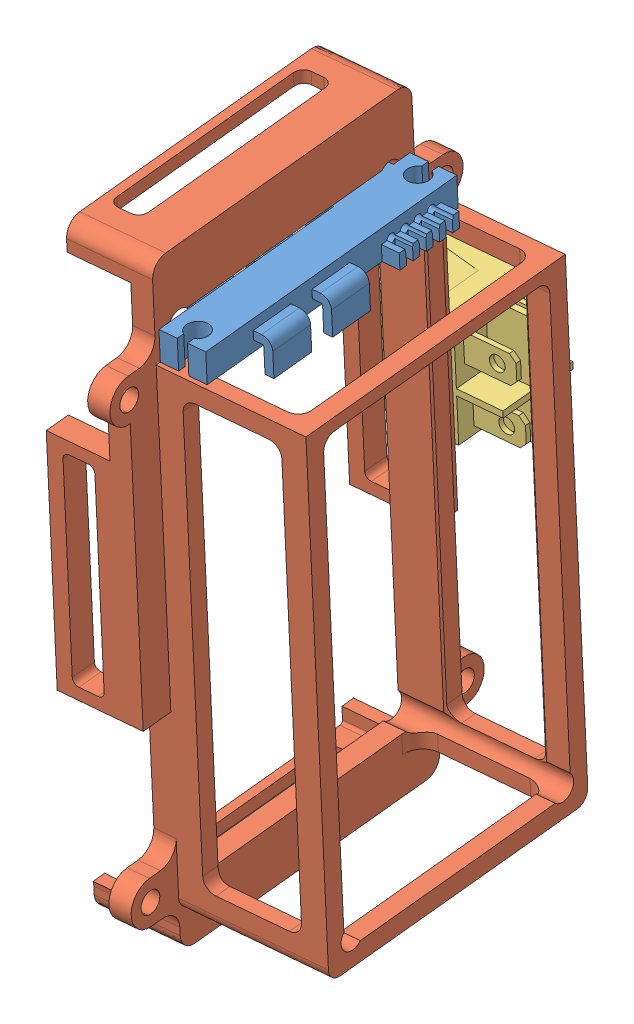
SolidWorks assembly 电池座模块, configuration 默认. Lengths in mm.
Overall size (50.65 103.56 77.6).
3 component instances, 3 part files, 6 mates.
Components (placement in the parent):
- DJI电池插头-1: DJI电池插头 [默认] at (-39.3968 69.1216 188.2199) x (-0.07178 0.029721 -0.996978) z (-0.017282 0.999369 0.031037) size (45.5 21.65 7.4)
- 大疆电池座-1: 大疆电池座 [默认] at (-45.994 26.6054 187.4275) x (-0.017282 0.999369 0.031037) z (-0.07178 0.029721 -0.996978) size (101 37 64)
- 开关-1: 开关 [默认] at (-56.2173 35.7381 153.4801) x (-0.017282 0.999369 0.031037) z (0.07178 -0.029721 0.996978) size (21.7 29.65 15.2)
Mates (geometry in assembly coordinates):
- 宽度1: width: plane of DJI电池插头-1 through (26.8803 -2.2512 88.6946) normal (0 0 -1); plane of DJI电池插头-1 through (26.8803 -2.2512 134.1946) normal (0 0 1); plane of 大疆电池座-1 through (-63.9207 2.7488 132.4446) normal (0 0 -1); plane of 大疆电池座-1 through (-63.9207 2.7488 90.4446) normal (0 0 1)
- 重合1: coincident: plane of DJI电池插头-1 through (22.0803 5.0988 111.4446) normal (-1 0 0); plane of 大疆电池座-1 through (22.0803 21.2488 87.9446) normal (1 0 0)
- 重合2: coincident: plane of DJI电池插头-1 through (26.8803 -2.2512 88.6946) normal (0 -1 0); plane of 大疆电池座-1 through (19.8303 -2.2512 139.9446) normal (0 1 0)
- 重合3: coincident: plane of 大疆电池座-1 through (-48.0397 27.4524 159.0136) normal (-0.07178 0.029721 -0.996978); plane of 开关-1 through (-54.0224 35.5833 159.6867) normal (0.07178 -0.029721 0.996978)
- 宽度2: width: plane of 开关-1 through (-47.4241 26.4647 158.9398) normal (0.017282 -0.999369 -0.031037); plane of 开关-1 through (-47.7438 44.9531 159.514) normal (-0.017282 0.999369 0.031037); plane of 大疆电池座-1 through (-99.7923 53.5602 167.5301) normal (-0.017282 0.999369 0.031037); plane of 大疆电池座-1 through (-47.8539 16.7092 158.68) normal (0.017282 -0.999369 -0.031037)
- 重合4: coincident: plane of 大疆电池座-1 through (-57.1979 -17.754 207.9754) normal (-0.997271 -0.019458 0.071222); plane of 开关-1 through (-62.1012 35.6233 153.9003) normal (0.997271 0.019458 -0.071222)
